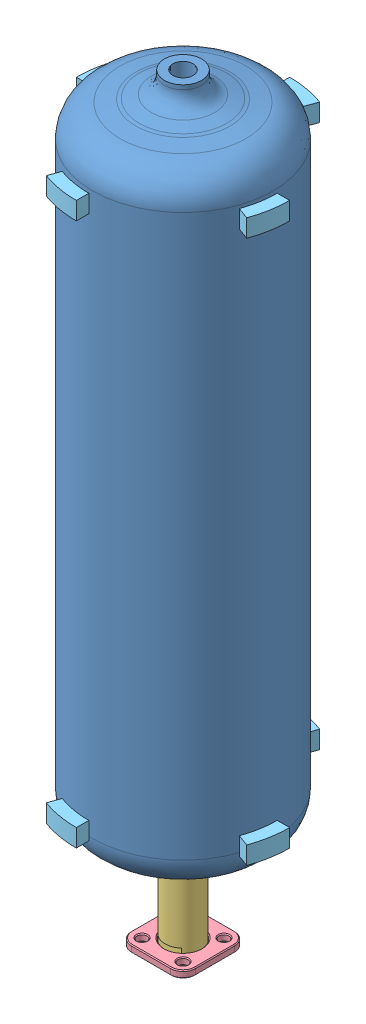
SolidWorks assembly P27_Alu_Ox_Tank, configuration Standard. Lengths in mm.
Overall size (126.8 436 126.8).
13 component instances, 5 part files, 17 mates.
Components (placement in the parent):
- P27_Alu_Ox_Tank-1: P27_Alu_Ox_Tank [Standard] at (0 383 0) size (101.6 383 101.6)
- P10_G_1-4_USIT_FKM-1: P10_G_1-4_USIT_FKM [Default] at (0 -2 0) size (20.6 2 20.6)
- P10_G_1-4_USIT_FKM-2: P10_G_1-4_USIT_FKM [Default] at (0 -50 0) size (20.6 2 20.6)
- Sub_P27_OxFlange-1: Sub_P27_OxFlange [Default] at (0 -48 0) size (27 61 27)
- Sub_P27_OxFlangeRetainer-1: Sub_P27_OxFlangeRetainer [Default] at (0 -44 0) size (36 4 36)
- P80_Spacer_OxTank-1: P80_Spacer_OxTank [Standard] at (0 339.29 0) x (0.34202 0 -0.939693) z (0.939693 0 0.34202) size (20.52 10 10.2)
- P80_Spacer_OxTank-6: P80_Spacer_OxTank [Standard] at (0 33.71 0) x (0.34202 0 -0.939693) z (0.939693 0 0.34202) size (20.52 10 10.2)
- P80_Spacer_OxTank-3: P80_Spacer_OxTank [Standard] at (0 339.29 0) x (-0.939693 0 -0.34202) z (0.34202 0 -0.939693) size (20.52 10 10.2)
- P80_Spacer_OxTank-4: P80_Spacer_OxTank [Standard] at (0 339.29 0) x (-0.34202 0 0.939693) z (-0.939693 0 -0.34202) size (20.52 10 10.2)
- P80_Spacer_OxTank-5: P80_Spacer_OxTank [Standard] at (0 339.29 0) x (0.939693 0 0.34202) z (-0.34202 0 0.939693) size (20.52 10 10.2)
- P80_Spacer_OxTank-7: P80_Spacer_OxTank [Standard] at (0 33.71 0) x (-0.939693 0 -0.34202) z (0.34202 0 -0.939693) size (20.52 10 10.2)
- P80_Spacer_OxTank-8: P80_Spacer_OxTank [Standard] at (0 33.71 0) x (-0.34202 0 0.939693) z (-0.939693 0 -0.34202) size (20.52 10 10.2)
- P80_Spacer_OxTank-9: P80_Spacer_OxTank [Standard] at (0 33.71 0) x (0.939693 0 0.34202) z (-0.34202 0 0.939693) size (20.52 10 10.2)
Mates (geometry in assembly coordinates):
- Konzentrisch1: concentric: cylinder of P27_Alu_Ox_Tank-1 through (0 403.1808 0) axis (0 1 0) radius 50.8
- Deckungsgleich3: coincident: plane of P27_Alu_Ox_Tank-1 through (0 0 0) normal (0 -1 0)
- Konzentrisch2: concentric aligned: cylinder of P27_Alu_Ox_Tank-1 through (0 0 0) axis (0 -1 0) radius 5.7225; cylinder of P10_G_1-4_USIT_FKM-1 through (0 0 0) axis (0 -1 0) radius 7
- Deckungsgleich4: coincident anti-aligned: plane of P27_Alu_Ox_Tank-1 through (0 0 0) normal (0 -1 0); plane of P10_G_1-4_USIT_FKM-1 through (0 0 0) normal (0 1 0)
- Konzentrisch3: concentric aligned: cylinder of P27_Alu_Ox_Tank-1 through (0 0 0) axis (0 -1 0) radius 5.7225; cylinder of Sub_P27_OxFlange-1 through (0 -48 0) axis (0 -1 0) radius 6.5
- Deckungsgleich5: coincident anti-aligned: plane of P10_G_1-4_USIT_FKM-1 through (0 -2 0) normal (0 -1 0); plane of Sub_P27_OxFlange-1 through (6.5 -2 0) normal (0 1 0)
- Konzentrisch4: concentric aligned: cylinder of P10_G_1-4_USIT_FKM-2 through (0 -48 0) axis (0 -1 0) radius 7; cylinder of Sub_P27_OxFlange-1 through (0 -48 0) axis (0 -1 0) radius 6.25
- Deckungsgleich6: coincident anti-aligned: plane of P10_G_1-4_USIT_FKM-2 through (0 -48 0) normal (0 1 0); plane of Sub_P27_OxFlange-1 through (13.5 -48 0) normal (0 -1 0)
- Konzentrisch5: concentric aligned: cylinder of Sub_P27_OxFlange-1 through (0 -48 0) axis (0 -1 0) radius 10; cylinder of Sub_P27_OxFlangeRetainer-1 through (0 -40 0) axis (0 -1 0) radius 10.25
- Parallel1: parallel aligned: plane of Sub_P27_OxFlange-1 through (-16.8308 -38 7.5) normal (0 0 1); plane of Sub_P27_OxFlangeRetainer-1 through (-11 -40 18) normal (0 0 1)
- Deckungsgleich8: coincident anti-aligned: plane of Sub_P27_OxFlange-1 through (10 -44 0) normal (0 1 0); plane of Sub_P27_OxFlangeRetainer-1 through (-11 -44 11) normal (0 -1 0)
- Konzentrisch6: concentric anti-aligned: cylinder of P27_Alu_Ox_Tank-1 through (0 403.1808 0) axis (0 1 0) radius 50.8; cylinder of Spacer_OxTank-2 through (0 43.71 0) axis (0 -1 0) radius 53
- Parallel2: parallel aligned: plane of Sub_P27_OxFlangeRetainer-1 through (-11 -40 18) normal (0 0 1); plane of Spacer_OxTank-2 through (-60 43.71 0) normal (0 0 1)
- Konzentrisch7: concentric anti-aligned: cylinder of P27_Alu_Ox_Tank-1 through (0 403.1808 0) axis (0 1 0) radius 50.8; cylinder of Spacer_OxTank-1 through (0 349.29 0) axis (0 -1 0) radius 53
- Parallel3: parallel aligned: plane of Sub_P27_OxFlangeRetainer-1 through (-11 -40 18) normal (0 0 1); plane of Spacer_OxTank-1 through (-60 349.29 0) normal (0 0 1)
- Deckungsgleich13: coincident anti-aligned: circle of P27_Alu_Ox_Tank-1; plane of Spacer_OxTank-2 through (0 33.71 0) normal (0 -1 0)
- Deckungsgleich14: coincident aligned: circle of P27_Alu_Ox_Tank-1; plane of Spacer_OxTank-1 through (0 349.29 0) normal (0 1 0)
